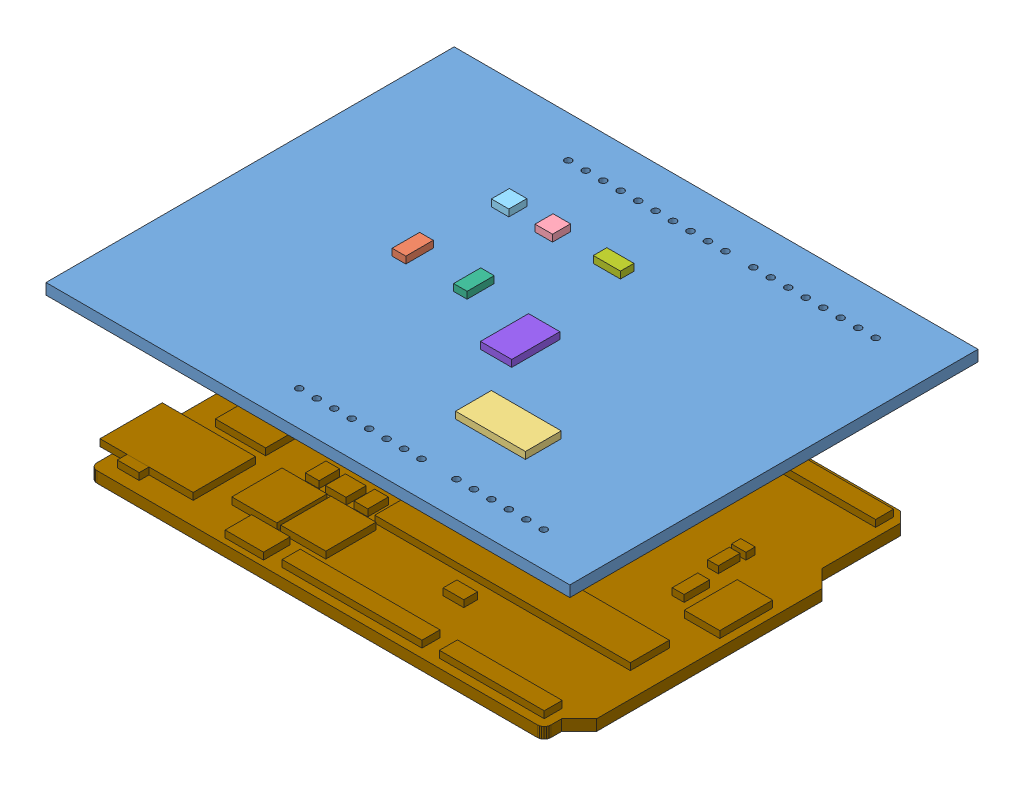
SolidWorks assembly initial_schematic_2, configuration Default. Lengths in mm.
Overall size (99.2 26.2 86.11).
9 component instances, 9 part files, 4 mates.
Components (placement in the parent):
- initial_schematic-1: initial_schematic [Default] x (1 0 0) z (0 1 0) size (76.18 59.36 1.6)
- C0805_C1_C0805-1: C0805_C1_C0805 [Default] at (57.15 1.6 -41.91) x (0 0 -1) z (0 1 0) size (4 1.99 1)
- AB9V_AB9V-1: AB9V_AB9V [Default] at (86.36 1.6 -26.67) x (0 0 -1) z (0 1 0) size (5.21 10.16 1)
- 1X01_JP1_1X01-1: 1X01_JP1_1X01 [Default] at (64.77 1.6 -54.61) x (1 0 0) z (0 1 0) size (2.54 2.62 1)
- 1X01_JP2_1X01-1: 1X01_JP2_1X01 [Default] at (58.42 1.6 -54.61) x (1 0 0) z (0 1 0) size (2.54 2.62 1)
- R0805W_50000-1: R0805W_50000 [Default] at (66.04 1.6 -41.91) x (0 0 1) z (0 1 0) size (3.95 1.97 1)
- R0805W_200-1: R0805W_200 [Default] at (73.66 1.6 -54.61) x (1 0 0) z (0 1 0) size (3.95 1.97 1)
- BTN_CK_KSS_SW1_BTN_CK_KSS-1: BTN_CK_KSS_SW1_BTN_CK_KSS [Default] at (76.2 1.6 -38.1) x (0 0 -1) z (0 1 0) size (7 4.55 1)
- arduino_uno_rev3-02-th-1: arduino_uno_rev3-02-th [Default] at (38.092 -22.6 -14.0446) x (1 0 0) z (0 1 0) size (89.77 77.71 3.6)
Mates (geometry in assembly coordinates):
- Distance1: distance = 20 mm: plane of arduino_uno_rev3-02-th-1 through (38.092 -20 -14.0446) normal (0 1 0); plane of initial_schematic-1 through (0 0 0) normal (0 -1 0)
- Distance7: distance = 0.762 mm: plane of arduino_uno_rev3-02-th-1 through (85.082 -20 -17.9308) normal (1 0 0); point of assembly
- Parallel1: parallel: plane of initial_schematic-1 through (34.29 1.6 -11.43) normal (0 0 1); plane of arduino_uno_rev3-02-th-1 through (103.132 -21 -14.0446) normal (0 0 1)
- Distance8: distance = 2.6146 mm: plane of initial_schematic-1 through (34.29 1.6 -11.43) normal (0 0 1); plane of arduino_uno_rev3-02-th-1 through (103.132 -21 -14.0446) normal (0 0 1)
